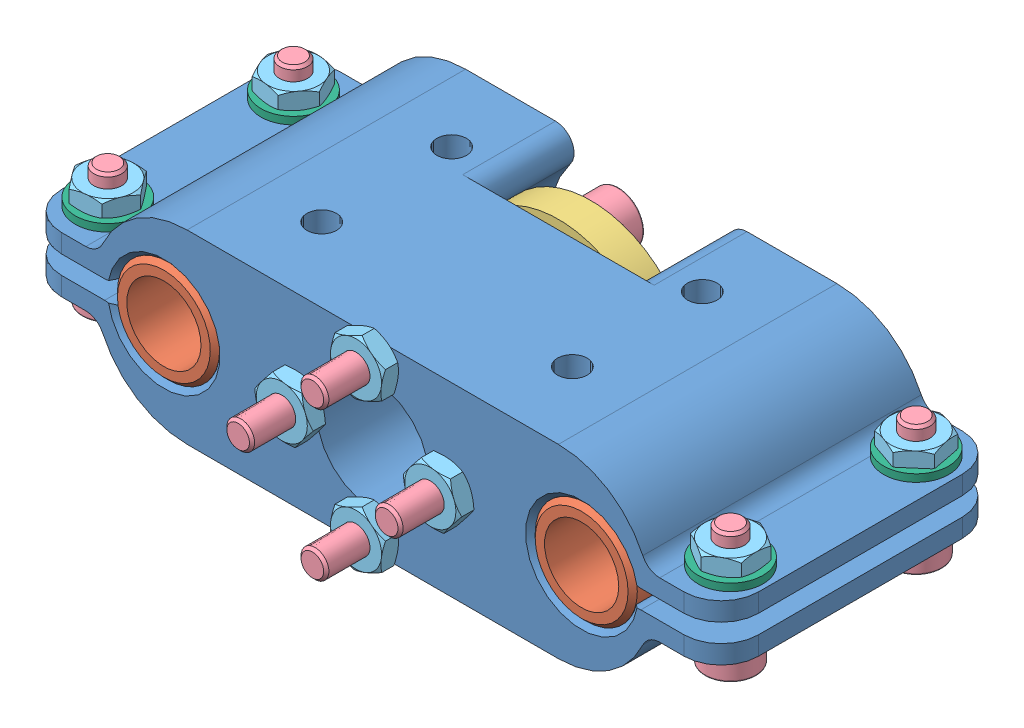
SolidWorks assembly X CHARIOT ASSY, configuration Default. Lengths in mm.
Overall size (75.18 23.51 36.69).
24 component instances, 6 part files, 34 mates.
Components (placement in the parent):
- lead x chariot-1: lead x chariot [Default] at (5.5588 3.7189 60.0788) size (75.08 20 30.38)
- brass sleeve 30mm-1: brass sleeve 30mm [Default] at (28.0588 3.7189 60.0788) size (11 11 30)
- brass sleeve 30mm-2: brass sleeve 30mm [Default] at (-16.9412 3.7189 60.0788) x (0.987351 0.158553 0) z (0 0 1) size (11 11 30)
- LeadScrew Nut 8mm x 2mmPitch (1)-1: LeadScrew Nut 8mm x 2mmPitch (1) [Default] at (5.5588 3.7189 66.5788) x (-1 0 0) z (0 0 -1) size (22 22 16.05)
- socket head cap screw_iso-2: socket head cap screw_iso [ISO 4762 M3 x 30 - 18N] at (-2.4412 3.7189 63.5788) x (0 0 1) z (0.923728 0.383049 0) size (33 5.5 5.5)
- socket head cap screw_iso-3: socket head cap screw_iso [ISO 4762 M3 x 30 - 18N] at (5.5588 11.7189 63.5788) x (0 0 1) z (0.383049 -0.923728 0) size (33 5.5 5.5)
- socket head cap screw_iso-4: socket head cap screw_iso [ISO 4762 M3 x 30 - 18N] at (13.5588 3.7189 63.5788) x (0 0 1) z (-0.923728 -0.383049 0) size (33 5.5 5.5)
- socket head cap screw_iso-5: socket head cap screw_iso [ISO 4762 M3 x 30 - 18N] at (5.5588 -4.2811 63.5788) x (0 0 1) z (-0.383049 0.923728 0) size (33 5.5 5.5)
- hex thin nut chamfered gradeab_iso-1: hex thin nut chamfered gradeab_iso [ISO - 4035 - M3 - N] at (13.5588 3.7189 90.0788) x (-0.923728 -0.383049 0) z (0 0 -1) size (5.5 6.35 1.8)
- hex thin nut chamfered gradeab_iso-2: hex thin nut chamfered gradeab_iso [ISO - 4035 - M3 - N] at (5.5588 -4.2811 90.0788) x (-0.383049 0.923728 0) z (0 0 -1) size (5.5 6.35 1.8)
- hex thin nut chamfered gradeab_iso-3: hex thin nut chamfered gradeab_iso [ISO - 4035 - M3 - N] at (-2.4412 3.7189 90.0788) x (0.923728 0.383049 0) z (0 0 -1) size (5.5 6.35 1.8)
- hex thin nut chamfered gradeab_iso-4: hex thin nut chamfered gradeab_iso [ISO - 4035 - M3 - N] at (5.5588 11.7189 90.0788) x (0.383049 -0.923728 0) z (0 0 -1) size (5.5 6.35 1.8)
- socket head cap screw_iso-6: socket head cap screw_iso [ISO 4762 M3 x 10 - 10N] at (39.0982 -2.2811 65.0788) x (0 1 0) z (0 0 1) size (13 5.5 5.5)
- socket head cap screw_iso-7: socket head cap screw_iso [ISO 4762 M3 x 10 - 10N] at (39.0982 -2.2811 85.0788) x (0 1 0) z (0.188455 0 0.982082) size (13 5.5 5.5)
- socket head cap screw_iso-8: socket head cap screw_iso [ISO 4762 M3 x 10 - 10N] at (-27.9806 -2.2811 65.0788) x (0 1 0) z (0.395734 0 0.918365) size (13 5.5 5.5)
- socket head cap screw_iso-9: socket head cap screw_iso [ISO 4762 M3 x 10 - 10N] at (-27.9806 -2.2811 85.0788) x (0 1 0) z (0.6 0 0.8) size (13 5.5 5.5)
- plain washer 10673 type snl_iso-1: plain washer 10673 type snl_iso [ISO 10673-3.2-S] at (39.0982 6.914 65.0788) x (0 1 0) z (0 0 1) size (0.8 7 7)
- plain washer 10673 type snl_iso-2: plain washer 10673 type snl_iso [ISO 10673-3.2-S] at (39.0982 6.7189 85.0788) x (0 1 0) z (0 0 1) size (0.8 7 7)
- plain washer 10673 type snl_iso-3: plain washer 10673 type snl_iso [ISO 10673-3.2-S] at (-27.9806 6.7189 65.0788) x (0 1 0) z (0 0 1) size (0.8 7 7)
- plain washer 10673 type snl_iso-4: plain washer 10673 type snl_iso [ISO 10673-3.2-S] at (-27.9806 6.7189 85.0788) x (0 1 0) z (0 0 1) size (0.8 7 7)
- hex thin nut chamfered gradeab_iso-6: hex thin nut chamfered gradeab_iso [ISO - 4035 - M3 - N] at (39.0982 7.5189 85.0788) x (1 0 0) z (0 -1 0) size (5.5 6.35 1.8)
- hex thin nut chamfered gradeab_iso-7: hex thin nut chamfered gradeab_iso [ISO - 4035 - M3 - N] at (39.0982 7.5189 65.0788) x (0.982082 0 -0.188455) z (0 -1 0) size (5.5 6.35 1.8)
- hex thin nut chamfered gradeab_iso-8: hex thin nut chamfered gradeab_iso [ISO - 4035 - M3 - N] at (-27.9806 7.5189 65.0788) x (0.918365 0 -0.395734) z (0 -1 0) size (5.5 6.35 1.8)
- hex thin nut chamfered gradeab_iso-9: hex thin nut chamfered gradeab_iso [ISO - 4035 - M3 - N] at (-27.9806 7.5189 85.0788) x (0.8 0 -0.6) z (0 -1 0) size (5.5 6.35 1.8)
Mates (geometry in assembly coordinates):
- Coincidente1: coincident aligned: plane of lead x chariot-1 through (5.5588 3.7189 60.0788) normal (0 0 -1); plane of brass sleeve 30mm-1 through (28.0588 3.7189 60.0788) normal (0 0 -1)
- Concentrico1: concentric anti-aligned: cylinder of lead x chariot-1 through (28.0588 3.7189 60.0778) axis (0 0 1) radius 5.05; cylinder of brass sleeve 30mm-1 through (28.0588 3.7189 90.0788) axis (0 0 -1) radius 5.5
- Coincidente2: coincident aligned: plane of lead x chariot-1 through (5.5588 3.7189 60.0788) normal (0 0 -1); plane of brass sleeve 30mm-2 through (-16.9412 3.7189 60.0788) normal (0 0 -1)
- Concentrico2: concentric anti-aligned: cylinder of lead x chariot-1 through (-16.9412 3.7189 60.0778) axis (0 0 1) radius 5.05; cylinder of brass sleeve 30mm-2 through (-16.9412 3.7189 90.0788) axis (0 0 -1) radius 5.5
- Coincidente5: coincident anti-aligned: plane of lead x chariot-1 through (5.5588 3.7189 70.0788) normal (0 0 -1); plane of LeadScrew Nut 8mm x 2mmPitch (1)-1 through (5.5588 3.7189 70.0788) normal (0 0 1)
- Concentrico3: concentric anti-aligned: cylinder of lead x chariot-1 through (5.5588 3.7189 60.0778) axis (0 0 1) radius 5.05; cylinder of LeadScrew Nut 8mm x 2mmPitch (1)-1 through (5.5588 3.7189 80.0788) axis (0 0 -1) radius 5.1
- Concentrico4: concentric anti-aligned: cylinder of lead x chariot-1 through (13.5588 3.7189 60.0778) axis (0 0 1) radius 1.6; cylinder of LeadScrew Nut 8mm x 2mmPitch (1)-1 through (13.5588 3.7189 70.0788) axis (0 0 -1) radius 1.75
- Concentrico5: concentric anti-aligned: cylinder of lead x chariot-1 through (-2.4412 3.7189 60.0778) axis (0 0 1) radius 1.6; cylinder of socket head cap screw_iso-2 through (-2.4412 3.7189 31.8288) axis (0 0 -1) radius 2.75
- Coincidente7: coincident anti-aligned: plane of LeadScrew Nut 8mm x 2mmPitch (1)-1 through (5.5588 3.7189 66.5788) normal (0 0 -1); plane of socket head cap screw_iso-2 through (-1.3878 1.1787 66.5788) normal (0 0 1)
- Concentrico8: concentric aligned: cylinder of socket head cap screw_iso-4 through (13.5588 3.7189 31.8288) axis (0 0 -1) radius 1.5; cylinder of hex thin nut chamfered gradeab_iso-1 through (13.5588 3.7189 115.1163) axis (0 0 -1) radius 1.5
- Coincidente9: coincident anti-aligned: plane of lead x chariot-1 through (5.5588 3.7189 90.0788) normal (0 0 1); plane of hex thin nut chamfered gradeab_iso-1 through (12.3425 6.6522 90.0788) normal (0 0 -1)
- Concentrico9: concentric aligned: cylinder of lead x chariot-1 through (39.0982 13.7199 65.0788) axis (0 -1 0) radius 1.6; cylinder of socket head cap screw_iso-6 through (39.0982 -34.0311 65.0788) axis (0 -1 0) radius 2.75
- Coincidente12: coincident aligned: plane of lead x chariot-1 through (35.0982 0.7189 50.0788) normal (0 -1 0); circle of socket head cap screw_iso-6
- Coincidente13: coincident aligned: plane of lead x chariot-1 through (35.0982 0.7189 50.0788) normal (0 -1 0); circle of socket head cap screw_iso-7
- Concentrico10: concentric aligned: cylinder of lead x chariot-1 through (39.0982 13.7199 85.0788) axis (0 -1 0) radius 1.6; cylinder of socket head cap screw_iso-7 through (39.0982 -34.0311 85.0788) axis (0 -1 0) radius 2.75
- Coincidente14: coincident aligned: plane of lead x chariot-1 through (35.0982 0.7189 50.0788) normal (0 -1 0); circle of socket head cap screw_iso-8
- Concentrico11: concentric aligned: cylinder of lead x chariot-1 through (-27.9806 13.7199 65.0788) axis (0 -1 0) radius 1.6; cylinder of socket head cap screw_iso-8 through (-27.9806 -34.0311 65.0788) axis (0 -1 0) radius 2.75
- Coincidente15: coincident aligned: plane of lead x chariot-1 through (35.0982 0.7189 50.0788) normal (0 -1 0); circle of socket head cap screw_iso-9
- Concentrico12: concentric aligned: cylinder of lead x chariot-1 through (-27.9806 13.7199 85.0788) axis (0 -1 0) radius 1.6; cylinder of socket head cap screw_iso-9 through (-27.9806 -34.0311 85.0788) axis (0 -1 0) radius 2.75
- Concentrico13: concentric aligned: cylinder of socket head cap screw_iso-6 through (39.0982 -34.0311 65.0788) axis (0 -1 0) radius 1.5; cylinder of plain washer 10673 type snl_iso-1 through (39.0982 7.714 65.0788) axis (0 -1 0) radius 1.6
- Concentrico14: concentric aligned: cylinder of lead x chariot-1 through (39.0982 13.7199 85.0788) axis (0 -1 0) radius 1.6; cylinder of plain washer 10673 type snl_iso-2 through (39.0982 7.5189 85.0788) axis (0 -1 0) radius 1.6
- Coincidente18: coincident anti-aligned: plane of lead x chariot-1 through (35.0982 6.7189 50.0788) normal (0 1 0); plane of plain washer 10673 type snl_iso-2 through (39.0982 6.7189 85.0788) normal (0 -1 0)
- Concentrico15: concentric aligned: cylinder of lead x chariot-1 through (-27.9806 13.7199 65.0788) axis (0 -1 0) radius 1.6; cylinder of plain washer 10673 type snl_iso-3 through (-27.9806 7.5189 65.0788) axis (0 -1 0) radius 1.6
- Coincidente19: coincident anti-aligned: plane of lead x chariot-1 through (-23.9806 6.7189 50.0788) normal (0 1 0); plane of plain washer 10673 type snl_iso-3 through (-27.9806 6.7189 65.0788) normal (0 -1 0)
- Concentrico16: concentric aligned: cylinder of lead x chariot-1 through (-27.9806 13.7199 85.0788) axis (0 -1 0) radius 1.6; cylinder of plain washer 10673 type snl_iso-4 through (-27.9806 7.5189 85.0788) axis (0 -1 0) radius 1.6
- Coincidente20: coincident anti-aligned: plane of lead x chariot-1 through (-23.9806 6.7189 50.0788) normal (0 1 0); plane of plain washer 10673 type snl_iso-4 through (-27.9806 6.7189 85.0788) normal (0 -1 0)
- Coincidente21: coincident anti-aligned: plane of plain washer 10673 type snl_iso-2 through (39.0982 7.5189 85.0788) normal (0 1 0); plane of hex thin nut chamfered gradeab_iso-6 through (39.0982 7.5189 88.2542) normal (0 -1 0)
- Concentrico17: concentric aligned: cylinder of socket head cap screw_iso-7 through (39.0982 -34.0311 85.0788) axis (0 -1 0) radius 1.5; cylinder of hex thin nut chamfered gradeab_iso-6 through (39.0982 9.3189 85.0788) axis (0 -1 0) radius 1.25
- Coincidente22: coincident anti-aligned: plane of plain washer 10673 type snl_iso-2 through (39.0982 7.5189 85.0788) normal (0 1 0); plane of hex thin nut chamfered gradeab_iso-7 through (39.6966 7.5189 68.1973) normal (0 -1 0)
- Concentrico18: concentric aligned: cylinder of socket head cap screw_iso-6 through (39.0982 -34.0311 65.0788) axis (0 -1 0) radius 1.5; cylinder of hex thin nut chamfered gradeab_iso-7 through (39.0982 9.3189 65.0788) axis (0 -1 0) radius 1.25
- Coincidente23: coincident anti-aligned: plane of plain washer 10673 type snl_iso-2 through (39.0982 7.5189 85.0788) normal (0 1 0); plane of hex thin nut chamfered gradeab_iso-8 through (-26.7239 7.5189 67.995) normal (0 -1 0)
- Concentrico19: concentric aligned: cylinder of socket head cap screw_iso-8 through (-27.9806 -34.0311 65.0788) axis (0 -1 0) radius 1.5; cylinder of hex thin nut chamfered gradeab_iso-8 through (-27.9806 9.3189 65.0788) axis (0 -1 0) radius 1.25
- Coincidente24: coincident anti-aligned: plane of plain washer 10673 type snl_iso-2 through (39.0982 7.5189 85.0788) normal (0 1 0); plane of hex thin nut chamfered gradeab_iso-9 through (-26.0753 7.5189 87.6191) normal (0 -1 0)
- Concentrico20: concentric aligned: cylinder of socket head cap screw_iso-9 through (-27.9806 -34.0311 85.0788) axis (0 -1 0) radius 1.5; cylinder of hex thin nut chamfered gradeab_iso-9 through (-27.9806 9.3189 85.0788) axis (0 -1 0) radius 1.25
